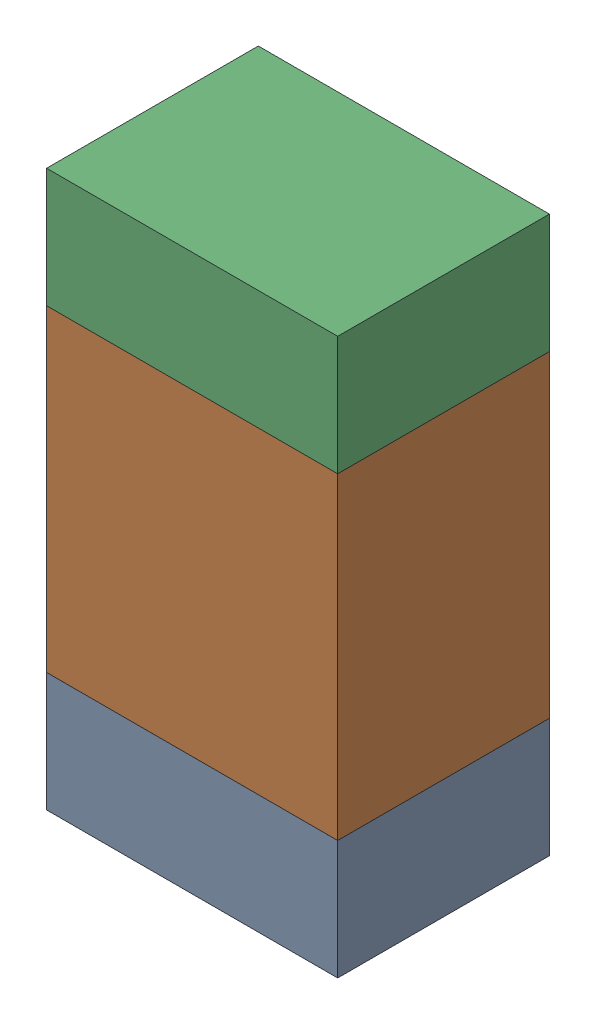
SolidWorks assembly R320_2PCB, configuration Default. Lengths in mm.
Overall size (0.55 1.05 0.4).
6 component instances, 2 part files, 0 mates.
Components (placement in the parent):
- 846483288-1: 846483288 [Default] at (130.3999 87.1874 -2.0638) size (0.55 0.22 0.4)
  - Extruded_12-1: Extruded_12 [Default] at origin size (0.55 0.22 0.4)
- 846483424-1: 846483424 [Default] at (130.3999 87.5999 -2.0638) size (0.55 0.6 0.4)
  - Extruded_13-1: Extruded_13 [Default] at origin size (0.55 0.6 0.4)
- 846483288-2: 846483288 [Default] at (130.3999 88.0124 -2.0638) size (0.55 0.22 0.4)
  - Extruded_12-1: Extruded_12 [Default] at origin size (0.55 0.22 0.4)
